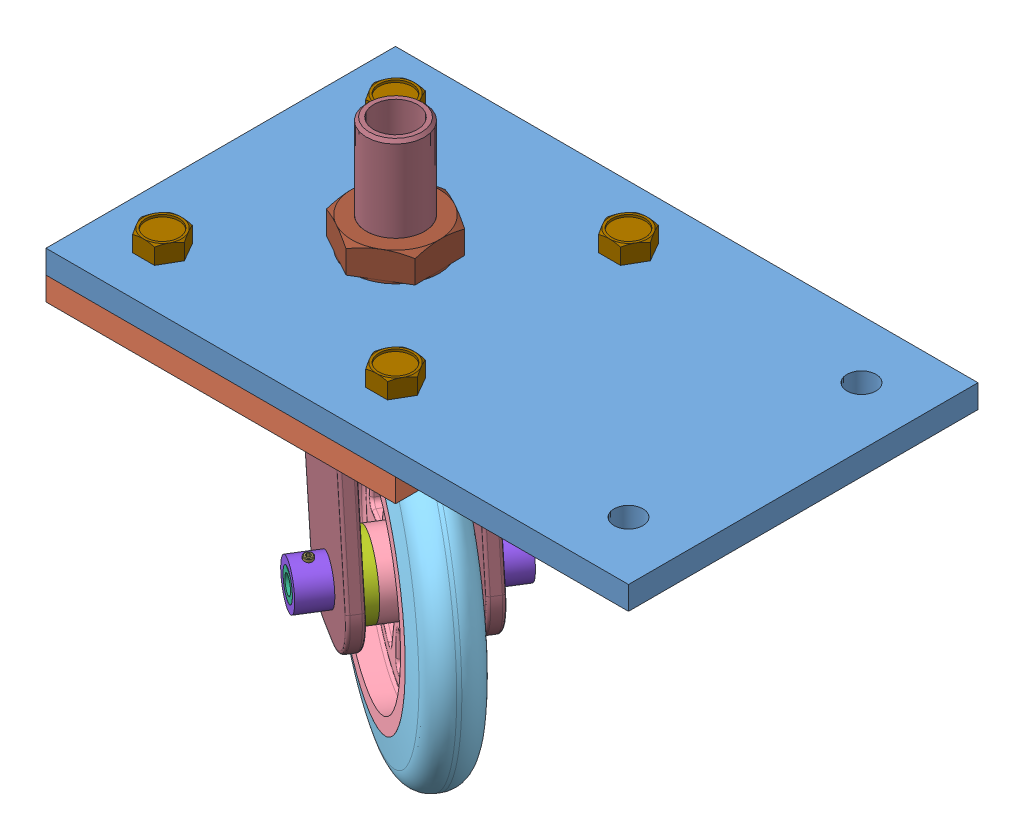
SolidWorks assembly angled caster.sldassm, configuration Default. Lengths in mm.
Overall size (200 207.67 126.14).
23 component instances, 13 part files, 24 mates.
Components (placement in the parent):
- Base.SLDPART.-1: Base.SLDPART. [Default] at (24.0932 107.2357 154.4264) size (200 8 120)
- Mount.-1: Mount. [Default] at (24.0932 99.2357 154.4264) size (120 8 120)
- Bearing-2: Bearing [Default] at (24.0932 94.2357 154.4264) x (0.99205 0 -0.125844) z (0 1 0) size (30 30 5)
- Wheel and Axle-1: Wheel and Axle [Default] at (95.6788 -23.5069 166.5511) x (-0.529038 0 0.848598) z (-0.836746 0.166547 -0.521649) size (60 110 110)
  - Wheel.-1: Wheel. [Default] at (27.5826 43.0888 61.6989) size (20 80 80)
  - Tire.-1: Tire. [Default] at (27.5826 43.0888 61.6989) size (20 110 110)
  - Axle.SLDPART-1: Axle.SLDPART [Default] at (27.5826 43.0888 61.6989) x (0 -0.083982 0.996467) z (-1 0 0) size (10 10 60)
  - Washer-1: Washer [Default] at (17.5826 43.0888 61.6989) x (0 0 1) z (-1 0 0) size (25 25 5)
  - Washer-2: Washer [Default] at (37.5826 43.0888 61.6989) x (0 -0.06397 -0.997952) z (1 0 0) size (25 25 5)
- Collar-1: Collar [Default] at (48.776 29.256 140.354) x (0.84566 -0.08315 0.527206) z (0.529038 0 -0.848598) size (15 15 10)
- Collar-2: Collar [Default] at (22.3241 29.256 182.7839) x (0.84566 -0.08315 0.527206) z (0.529038 0 -0.848598) size (15 15 10)
- hex screw_am-2: hex screw_am [B18.6.7M - M8 x 1.25 x 25 Indented HHMS --25N] at (-15.9068 121.2357 114.4264) x (0 -1 0) z (0 0 1) size (31 15.01 13)
- hex nut style 1_am-4: hex nut style 1_am [B18.2.4.1M - Hex nut, Style 1,  M8 x 1.25 --D-N] at (-15.9068 99.2357 114.4264) x (0.998244 0 0.059238) z (0 1 0) size (13 15.01 6.8)
- hex nut style 1_am-5: hex nut style 1_am [B18.2.4.1M - Hex nut, Style 1,  M8 x 1.25 --D-N] at (64.0932 99.2357 114.4264) x (0.998244 0 0.059238) z (0 1 0) size (13 15.01 6.8)
- hex nut style 1_am-6: hex nut style 1_am [B18.2.4.1M - Hex nut, Style 1,  M8 x 1.25 --D-N] at (-15.9068 99.2357 194.4264) x (0.998244 0 0.059238) z (0 1 0) size (13 15.01 6.8)
- hex nut style 1_am-7: hex nut style 1_am [B18.2.4.1M - Hex nut, Style 1,  M8 x 1.25 --D-N] at (64.0932 99.2357 194.4264) x (0.998244 0 0.059238) z (0 1 0) size (13 15.01 6.8)
- hex screw_am-3: hex screw_am [B18.6.7M - M8 x 1.25 x 25 Indented HHMS --25N] at (64.0932 121.2357 114.4264) x (0 -1 0) z (0 0 1) size (31 15.01 13)
- hex screw_am-4: hex screw_am [B18.6.7M - M8 x 1.25 x 25 Indented HHMS --25N] at (-15.9068 121.2357 194.4264) x (0 -1 0) z (0 0 1) size (31 15.01 13)
- hex screw_am-5: hex screw_am [B18.6.7M - M8 x 1.25 x 25 Indented HHMS --25N] at (64.0932 121.2357 194.4264) x (0 -1 0) z (0 0 1) size (31 15.01 13)
- hex nut jam_am-1: hex nut jam_am [B18.2.4.5M - Hex jam nut,  M20 x 2.5 --W-N] at (24.0932 125.2357 154.4264) x (0.999846 0 -0.017538) z (0 1 0) size (30 34.64 10)
- socket set screw flat point_am-3: socket set screw flat point_am [B18.3.6M - M3 x 0.5 x 4 Hex Socket Flat Pt. SS --N] at (49.3758 37.7265 140.7279) x (-0.070561 -0.996537 -0.04399) z (0.589685 -0.077241 0.803931) size (4 3 3)
- socket set screw flat point_am-4: socket set screw flat point_am [B18.3.6M - M3 x 0.5 x 4 Hex Socket Flat Pt. SS --N] at (22.9239 37.7265 183.1578) x (-0.070561 -0.996537 -0.04399) z (-0.979837 0.077508 -0.184151) size (4 3 3)
- Fork-1: Fork [Default] at (24.0932 94.2357 154.4264) x (-0.848598 0 -0.529038) z (-0.529038 0 0.848598) size (80 207.67 80)
Mates (geometry in assembly coordinates):
- Concentric1: concentric aligned: cylinder of Base.SLDPART.-1 through (24.0932 107.2357 154.4264) axis (0 1 0) radius 12.5; cylinder of Mount.-1 through (24.0932 99.2357 154.4264) axis (0 1 0) radius 12.5
- Concentric2: concentric aligned: cylinder of Base.SLDPART.-1 through (-15.9068 107.2357 114.4264) axis (0 1 0) radius 5; cylinder of Mount.-1 through (-15.9068 99.2357 114.4264) axis (0 1 0) radius 5
- Concentric3: concentric aligned: cylinder of Base.SLDPART.-1 through (64.0932 107.2357 114.4264) axis (0 1 0) radius 5; cylinder of Mount.-1 through (64.0932 99.2357 114.4264) axis (0 1 0) radius 5
- Coincident3: coincident anti-aligned: plane of Base.SLDPART.-1 through (24.0932 107.2357 154.4264) normal (0 -1 0); plane of Mount.-1 through (24.0932 107.2357 154.4264) normal (0 1 0)
- Concentric7: concentric anti-aligned: cylinder of Mount.-1 through (24.0932 99.2357 154.4264) axis (0 1 0) radius 12.5; cylinder of Bearing-2 through (24.0932 99.2357 154.4264) axis (0 -1 0) radius 10
- Coincident5: coincident anti-aligned: plane of Mount.-1 through (24.0932 99.2357 154.4264) normal (0 -1 0); plane of Bearing-2 through (24.0932 99.2357 154.4264) normal (0 1 0)
- Concentric10: concentric aligned: cylinder of Wheel and Axle-1/Axle.SLDPART-1 through (51.4212 29.256 136.111) axis (-0.529038 0 0.848598) radius 5; cylinder of Collar-2 through (24.9693 29.256 178.5409) axis (-0.529038 0 0.848598) radius 5
- Parallel2: parallel anti-aligned: plane of Wheel and Axle-1/Axle.SLDPART-1 through (27.1299 33.5592 179.8879) normal (0.070561 0.996537 0.04399); plane of Collar-2 through (22.3241 29.256 182.7839) normal (-0.070561 -0.996537 -0.04399)
- Concentric11: concentric aligned: cylinder of Wheel and Axle-1/Axle.SLDPART-1 through (51.4212 29.256 136.111) axis (-0.529038 0 0.848598) radius 5; cylinder of Collar-1 through (51.4212 29.256 136.111) axis (-0.529038 0 0.848598) radius 5
- Parallel3: parallel anti-aligned: plane of Wheel and Axle-1/Axle.SLDPART-1 through (48.2914 33.5592 145.944) normal (0.070561 0.996537 0.04399); plane of Collar-1 through (48.776 29.256 140.354) normal (-0.070561 -0.996537 -0.04399)
- Concentric12: concentric aligned: cylinder of Base.SLDPART.-1 through (-15.9068 107.2357 114.4264) axis (0 1 0) radius 5; cylinder of hex screw_am-2 through (-15.9068 146.6357 114.4264) axis (0 1 0) radius 4
- Coincident15: coincident anti-aligned: plane of Base.SLDPART.-1 through (24.0932 115.2357 154.4264) normal (0 1 0); plane of hex screw_am-2 through (-11.9068 115.2357 114.4264) normal (0 -1 0)
- Concentric15: concentric aligned: cylinder of hex screw_am-2 through (-15.9068 146.6357 114.4264) axis (0 1 0) radius 4; cylinder of hex nut style 1_am-4 through (-15.9068 74.1982 114.4264) axis (0 1 0) radius 4
- Coincident201: coincident anti-aligned: plane of Mount.-1 through (24.0932 99.2357 154.4264) normal (0 -1 0); plane of hex nut style 1_am-4 through (-15.4622 99.2357 106.9341) normal (0 1 0)
- Coincident221: coincident anti-aligned: plane of Wheel and Axle-1/Axle.SLDPART-1 through (48.2914 33.5592 145.944) normal (0.070561 0.996537 0.04399); plane of socket set screw flat point_am-3 through (49.8981 33.7096 139.9589) normal (-0.070561 -0.996537 -0.04399)
- Concentric171: concentric anti-aligned: cylinder of Collar-1 through (49.3053 36.731 140.684) axis (-0.070561 -0.996537 -0.04399) radius 1.5; cylinder of socket set screw flat point_am-3 through (50.2719 50.3826 141.2866) axis (0.070561 0.996537 0.04399) radius 1.5
- Coincident231: coincident anti-aligned: plane of Wheel and Axle-1/Axle.SLDPART-1 through (27.1299 33.5592 179.8879) normal (0.070561 0.996537 0.04399); plane of socket set screw flat point_am-4 through (22.4547 33.7103 183.9638) normal (-0.070561 -0.996537 -0.04399)
- Concentric181: concentric anti-aligned: cylinder of Collar-2 through (22.8534 36.731 183.1139) axis (-0.070561 -0.996537 -0.04399) radius 1.5; cylinder of socket set screw flat point_am-4 through (23.82 50.3826 183.7165) axis (0.070561 0.996537 0.04399) radius 1.5
- Concentric182: concentric anti-aligned: cylinder of Base.SLDPART.-1 through (24.0932 107.2357 154.4264) axis (0 1 0) radius 12.5; cylinder of Fork-1 through (24.0932 154.2357 154.4264) axis (0 -1 0) radius 10
- Coincident232: coincident anti-aligned: plane of Bearing-2 through (24.0932 94.2357 154.4264) normal (0 -1 0); plane of Fork-1 through (24.0932 94.2357 154.4264) normal (0 1 0)
- Concentric183: concentric aligned: cylinder of Wheel and Axle-1/Axle.SLDPART-1 through (51.4212 29.256 136.111) axis (-0.529038 0 0.848598) radius 5; cylinder of Fork-1 through (53.6125 29.256 132.596) axis (-0.529038 0 0.848598) radius 5
- Coincident233: coincident anti-aligned: plane of Wheel and Axle-1/Washer-2 through (27.6145 29.256 174.2979) normal (-0.529038 0 0.848598); plane of Fork-1 through (13.8582 13.256 165.7219) normal (0.529038 0 -0.848598)
- Coincident234: coincident anti-aligned: plane of Collar-2 through (24.9693 29.256 178.5409) normal (0.529038 0 -0.848598); plane of Fork-1 through (11.213 13.256 169.9649) normal (-0.529038 0 0.848598)
- Coincident235: coincident anti-aligned: plane of Collar-1 through (46.1308 29.256 144.597) normal (-0.529038 0 0.848598); plane of Fork-1 through (32.3746 13.256 136.021) normal (0.529038 0 -0.848598)
